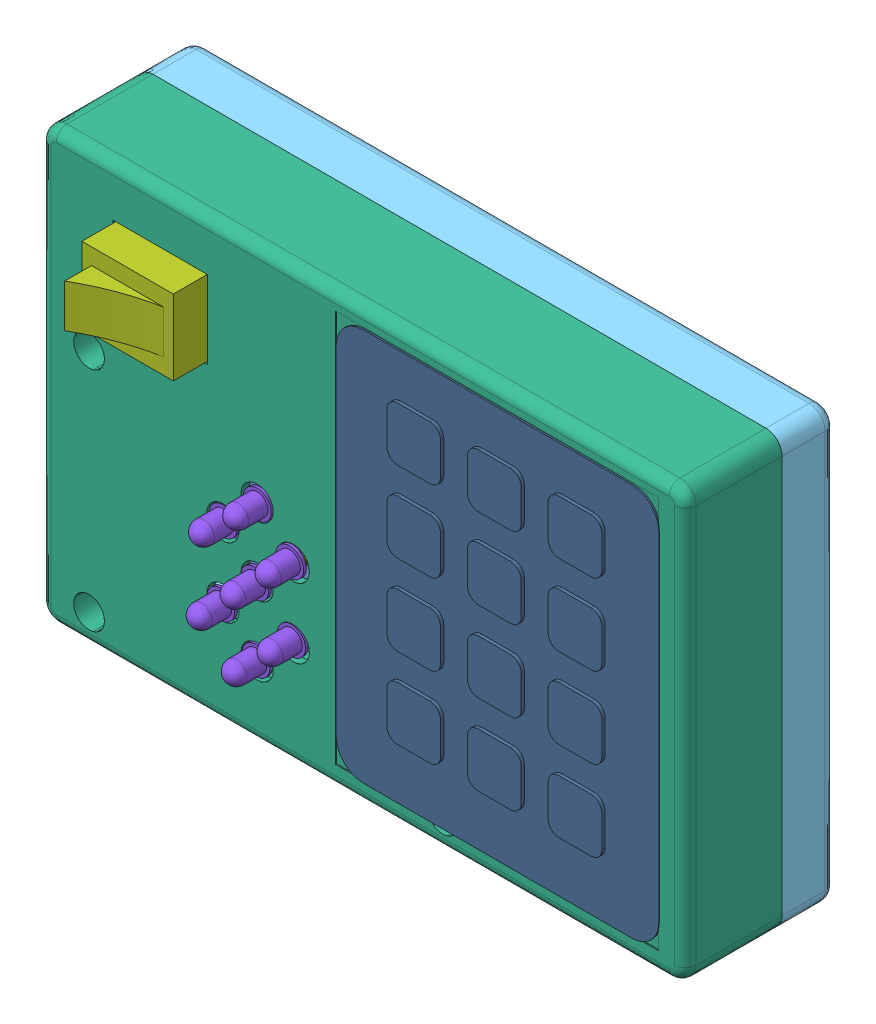
SolidWorks assembly Key_Input, configuration Default. Lengths in mm.
Overall size (120 80 38.81).
36 component instances, 10 part files, 22 mates.
Components (placement in the parent):
- Key_Input.step-1: Key_Input.step [Default] at origin size (78.49 50.8 20.11)
  - Board.step-1: Board.step [Default] at origin size (78.49 50.8 0.41)
    - Open CASCADE STEP translator 6.8 1.1.1.step-1: Open CASCADE STEP translator 6.8 1.1.1.step [Default] at (0 0 -0.4115) size (78.49 50.8 0.41)
  - U1.step-1: U1.step [Default] at origin size (7.2 35.3 4.58)
    - 6384015440.step-1: 6384015440.step [Default] at (131.826 74.93 0) size (7.2 35.3 4.58)
      - Extruded.step-1: Extruded.step [Default] at origin size (7.2 35.3 4.58)
  - U3.step-1: U3.step [Default] at origin size (10.5 4.7 16.2)
    - 6384015040.step-1: 6384015040.step [Default] at (88.265 83.226 13.05) size (10.4 1.3 6.65)
      - Extruded-0.step-1: Extruded-0.step [Default] at origin size (10.4 1.3 6.65)
    - 6384014640.step-1: 6384014640.step [Default] at (88.265 81.576 3.5) size (10.5 4.7 9.55)
      - Extruded-1.step-1: Extruded-1.step [Default] at origin size (10.5 4.7 9.55)
- Part1^Key_Input-1: Part1^Key_Input [Default] at (0 0 -0.4115) x (-1 0 0) z (0 0 -1) size (120 80 16.5) (virtual)
- Part2^Key_Input-1: Part2^Key_Input [Default] at (0 0 4.5885) size (120 80 22.59) (virtual)
- switch-1: switch [Default] at (100.5986 120.1142 18.3999) x (-1 0 0) z (0 1 0) size (17 23 14)
- led_full-3: led_full [Default] at (100.8932 99.3259 -3.8462) x (0.99328 0.115739 0) z (0.115739 -0.99328 0) size (5.2 32.34 5.2)
  - led2-1: led2 [Default] at (-172.081 10.1513 24.3661) size (5.2 6.1 5.2)
  - led-2: led [Default] at (5.5552 15.5162 24.092) size (3.04 28.26 0.5)
- led_full-4: led_full [Default] at (92.0642 77.0025 -4.0639) x (0.060823 0.998149 0) z (0.998149 -0.060823 0) size (5.2 32.34 5.2)
  - led2-1: led2 [Default] at (-172.081 10.1513 24.3661) size (5.2 6.1 5.2)
  - led-2: led [Default] at (5.5552 15.5162 24.092) size (3.04 28.26 0.5)
- led_full-5: led_full [Default] at (121.5765 65.7094 -4.1373) x (-0.985601 -0.169087 0) z (-0.169087 0.985601 0) size (5.2 32.34 5.2)
  - led2-1: led2 [Default] at (-172.081 10.1513 24.3661) size (5.2 6.1 5.2)
  - led-2: led [Default] at (5.5552 15.5162 24.092) size (3.04 28.26 0.5)
- led_full-6: led_full [Default] at (92.6159 62.448 -4.3342) x (-0.01402 0.999902 0) z (0.999902 0.01402 0) size (5.2 32.34 5.2)
  - led2-1: led2 [Default] at (-172.081 10.1513 24.3661) size (5.2 6.1 5.2)
  - led-2: led [Default] at (5.5552 15.5162 24.092) size (3.04 28.26 0.5)
- led_full-7: led_full [Default] at (128.1286 90.6228 -4.3312) x (0.052392 -0.998627 0) z (-0.998627 -0.052392 0) size (5.2 32.34 5.2)
  - led2-1: led2 [Default] at (-172.081 10.1513 24.3661) size (5.2 6.1 5.2)
  - led-2: led [Default] at (5.5552 15.5162 24.092) size (3.04 28.26 0.5)
- led_full-8: led_full [Default] at (80.5029 59.6308 -4.0919) x (-0.110312 0.993897 0) z (0.993897 0.110312 0) size (5.2 32.34 5.2)
  - led2-1: led2 [Default] at (-172.081 10.1513 24.3661) size (5.2 6.1 5.2)
  - led-2: led [Default] at (5.5552 15.5162 24.092) size (3.04 28.26 0.5)
- led_full-9: led_full [Default] at (104.4178 87.9355 -4.0438) x (0.999561 -0.029614 0) z (-0.029614 -0.999561 0) size (5.2 32.34 5.2)
  - led2-1: led2 [Default] at (-172.081 10.1513 24.3661) size (5.2 6.1 5.2)
  - led-2: led [Default] at (5.5552 15.5162 24.092) size (3.04 28.26 0.5)
- keypad-1: keypad [Default] at (168.9295 84.4724 22.3885) x (1 0 0) z (0 -1 0) size (60 0.9 73)
Mates (geometry in assembly coordinates):
- InPlace1: in place: plane of Key_Input.step-1/Board.step-1/Open CASCADE STEP translator 6.8 1.1.1.step-1 through (72.009 51.816 -0.4115) normal (0 0 -1); plane of Part1^Key_Input-1 through (0 0 -0.4115) normal (0 0 -1); moOrthogonalPlaneRef_w of Key_Input.step-1/Board.step-1/Open CASCADE STEP translator 6.8 1.1.1.step-1 through (72.009 51.816 -0.4115) normal (0 0 -1); plane of Part1^Key_Input-1 through (0 0 -0.4115) normal (0 1 0); plane of Key_Input.step-1/Board.step-1/Open CASCADE STEP translator 6.8 1.1.1.step-1 through (72.009 51.816 -0.4115) normal (0 0 -1); plane of Part1^Key_Input-1 through (0 0 -0.4115) normal (-1 0 0); plane of Key_Input.step-1/Board.step-1/Open CASCADE STEP translator 6.8 1.1.1.step-1 through (72.009 51.816 -0.4115) normal (0 0 -1); unknown of Part1^Key_Input-1
- Coincident1: coincident aligned: plane of Key_Input.step-1/Board.step-1/Open CASCADE STEP translator 6.8 1.1.1.step-1; plane of Part1^Key_Input-1
- Coincident2: coincident aligned: moOrthogonalPlaneRef_w of Key_Input.step-1/Board.step-1/Open CASCADE STEP translator 6.8 1.1.1.step-1 through (0 0 -0.4115) normal (0 1 0); plane of Part1^Key_Input-1 through (0 0 -0.4115) normal (0 1 0)
- Coincident3: coincident anti-aligned: moOrthogonalPlaneRef_w of Key_Input.step-1/Board.step-1/Open CASCADE STEP translator 6.8 1.1.1.step-1 through (0 0 -0.4115) normal (1 0 0); plane of Part1^Key_Input-1 through (0 0 -0.4115) normal (-1 0 0)
- InPlace2: in place: plane of Part1^Key_Input-1 through (0 0 4.5885) normal (0 0 1); plane of Part2^Key_Input-1 through (0 0 4.5885) normal (0 0 1); plane of Part1^Key_Input-1 through (0 0 4.5885) normal (0 0 1); plane of Part2^Key_Input-1 through (0 0 4.5885) normal (0 1 0); plane of Part1^Key_Input-1 through (0 0 4.5885) normal (0 0 1); plane of Part2^Key_Input-1 through (0 0 4.5885) normal (1 0 0); plane of Part1^Key_Input-1 through (0 0 4.5885) normal (0 0 1); unknown of Part2^Key_Input-1
- Coincident1: coincident aligned: plane of Part1^Key_Input-1; plane of Part2^Key_Input-1
- Coincident2: coincident aligned: moOrthogonalPlaneRef_w of Part1^Key_Input-1 through (0 0 4.5885) normal (0 1 0); plane of Part2^Key_Input-1 through (0 0 4.5885) normal (0 1 0)
- Coincident3: coincident anti-aligned: moOrthogonalPlaneRef_w of Part1^Key_Input-1 through (0 0 4.5885) normal (-1 0 0); plane of Part2^Key_Input-1 through (0 0 4.5885) normal (1 0 0)
- Coincident3: coincident: line of Part2^Key_Input-1 through (83.5986 106.1142 22.5885) axis (1 0 0); plane of switch-1 through (100.5986 106.1142 28.3999) normal (0 -1 0)
- Coincident8: coincident: line of Part2^Key_Input-1 through (83.5986 106.1142 22.5885) axis (1 0 0); plane of switch-1 through (100.5986 106.1142 28.3999) normal (0 -1 0)
- Coincident10: coincident anti-aligned: plane of Part2^Key_Input-1 through (83.5986 106.1142 21.0885) normal (0 1 0); plane of switch-1 through (100.5986 106.1142 28.3999) normal (0 -1 0)
- Parallel2: parallel anti-aligned: plane of Part2^Key_Input-1 through (83.5986 120.6142 21.0885) normal (0 -1 0); plane of switch-1 through (100.5986 120.1142 28.3999) normal (0 1 0)
- Coincident15: coincident anti-aligned: plane of Part2^Key_Input-1 through (83.5986 120.6142 21.0885) normal (1 0 0); plane of switch-1 through (83.5986 120.1142 28.3999) normal (-1 0 0)
- Coincident16: coincident anti-aligned: plane of Part2^Key_Input-1 through (83.5986 120.6142 21.0885) normal (1 0 0); plane of switch-1 through (83.5986 120.1142 28.3999) normal (-1 0 0)
- Concentric2: concentric anti-aligned: circle of Key_Input.step-1/Board.step-1/Open CASCADE STEP translator 6.8 1.1.1.step-1; line of led_full-3/led-2 through (111.633 75.819 23.1987) axis (0 0 -1)
- Concentric3: concentric anti-aligned: circle of Key_Input.step-1/Board.step-1/Open CASCADE STEP translator 6.8 1.1.1.step-1; line of led_full-4/led-2 through (117.094 83.439 22.981) axis (0 0 -1)
- Concentric4: concentric aligned: circle of Key_Input.step-1/Board.step-1/Open CASCADE STEP translator 6.8 1.1.1.step-1; line of led_full-5/led-2 through (109.093 88.519 -3.8386) axis (0 0 1)
- Concentric5: concentric anti-aligned: circle of Key_Input.step-1/Board.step-1/Open CASCADE STEP translator 6.8 1.1.1.step-1; line of led_full-6/led-2 through (117.094 70.739 22.7108) axis (0 0 -1)
- Concentric6: concentric aligned: circle of Key_Input.step-1/Board.step-1/Open CASCADE STEP translator 6.8 1.1.1.step-1; line of led_full-7/led-2 through (104.013 80.899 -4.0324) axis (0 0 1)
- Concentric7: concentric aligned: circle of Key_Input.step-1/Board.step-1/Open CASCADE STEP translator 6.8 1.1.1.step-1; line of led_full-8/led-2 through (104.013 70.739 -3.7931) axis (0 0 1)
- Concentric8: concentric anti-aligned: circle of Key_Input.step-1/Board.step-1/Open CASCADE STEP translator 6.8 1.1.1.step-1; line of led_full-9/led-2 through (111.633 63.119 23.0012) axis (0 0 -1)
- Coincident17: coincident anti-aligned: plane of Part2^Key_Input-1 through (0 0 22.3885) normal (0 0 1); plane of keypad-1 through (168.9295 84.4724 22.3885) normal (0 0 -1)
